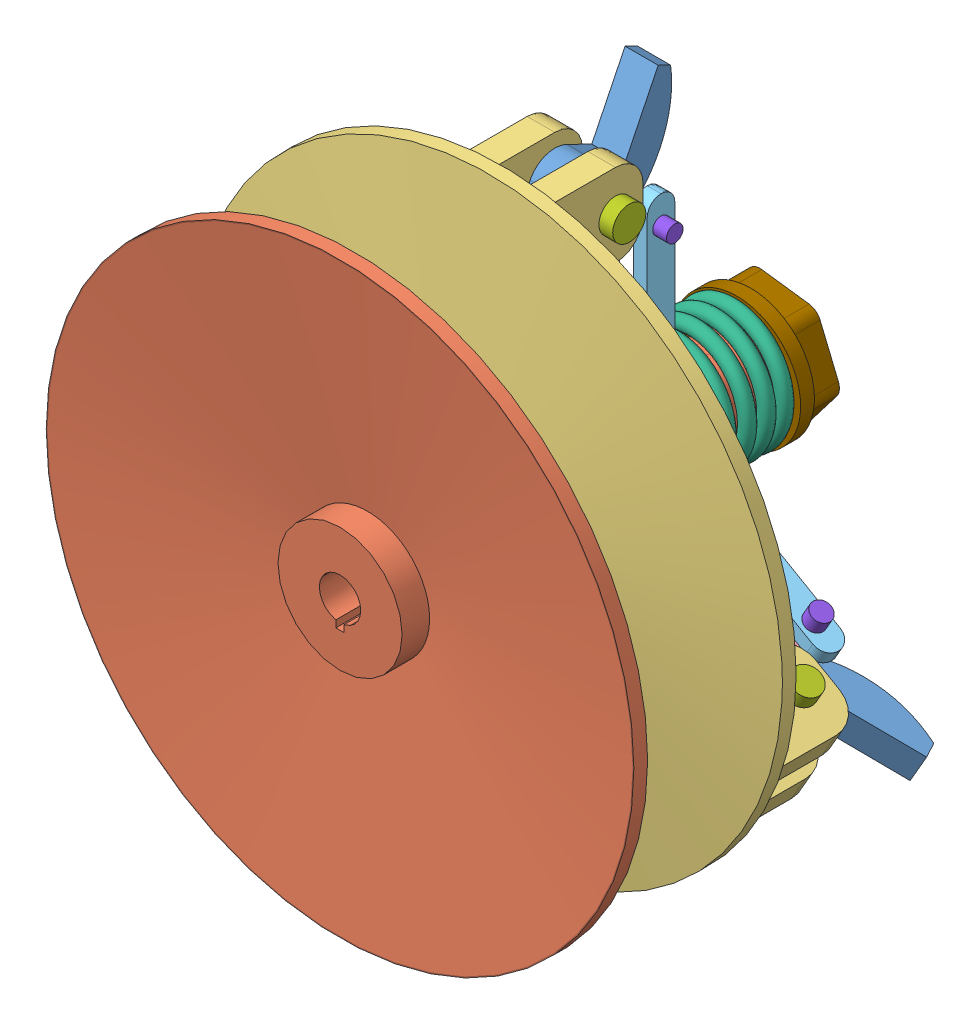
SolidWorks assembly Assembly primary pulley, configuration Default. Lengths in mm.
Overall size (221.83 231.11 158.84).
17 component instances, 9 part files, 40 mates.
Components (placement in the parent):
- cam-1: cam [Default] at (-288.314 -18.7579 216.225) x (0 0.898113 -0.439766) z (-1 0 0) size (47.5 32.18 12)
- primary fix pulley-1: primary fix pulley [Default] at (-294.314 -109.6854 231.0949) size (213 213 158.84)
- primary movable pulley-1: primary movable pulley [Default] at (-294.314 -109.6854 232.2585) size (213 213 50)
- roller-1: roller [Default] at (-286.814 -38.1854 187.2585) x (0 0 1) z (-1 0 0) size (12 12 15)
- spider-1: spider [Default] at (-294.314 -109.6854 182.2585) size (153.66 133.08 15)
- spring-1: spring [Default] at (-294.3124 -109.6827 147.2585) x (-0.215743 -0.97645 0) z (-0.97645 0.215743 0) size (46.49 35 46.31)
- temo bolt 10-1: temo bolt 10 [Default] at (-315.314 -23.1854 207.2585) x (0 -0.924225 -0.381849) z (1 0 0) size (12 12 42)
- temp bolt 6-1: temp bolt 6 [Default] at (-306.814 -38.1854 187.2585) x (0 0 -1) z (1 0 0) size (7 7 35)
- temo bolt 10-27: temo bolt 10 [Default] at (-358.7252 -171.122 207.2585) x (-0.862029 -0.497693 -0.09596) z (-0.5 0.866025 0) size (12 12 42)
- cam-27: cam [Default] at (-376.0596 -149.9531 216.225) x (-0.777788 -0.449056 -0.439766) z (0.5 -0.866025 0) size (47.5 32.18 12)
- cam-28: cam [Default] at (-218.5685 -160.3454 216.225) x (0.777788 -0.449056 -0.439766) z (0.5 0.866025 0) size (47.5 32.18 12)
- temo bolt 10-28: temo bolt 10 [Default] at (-208.9028 -134.7489 207.2585) x (-0.860588 0.496861 0.111883) z (-0.5 -0.866025 0) size (12 12 42)
- temp bolt 6-2: temp bolt 6 [Default] at (-349.9848 -156.2608 187.2585) x (-0.355611 -0.205312 -0.911805) z (-0.5 0.866025 0) size (7 7 35)
- roller-2: roller [Default] at (-352.4848 -151.9306 187.2585) x (0.738529 0.42639 -0.522271) z (-0.5 0.866025 0) size (12 12 15)
- temp bolt 6-4: temp bolt 6 [Default] at (-226.1432 -134.6101 187.2585) x (-0.455022 0.262707 -0.850846) z (-0.5 -0.866025 0) size (7 7 35)
- roller-4: roller [Default] at (-228.6432 -138.9403 187.2585) x (0.833101 -0.480991 -0.273113) z (-0.5 -0.866025 0) size (12 12 15)
- Lockpin-1: Lockpin [Default] at (-294.314 -109.6854 142.2585) x (-0.923728 -0.383049 0) z (0 0 -1) size (46.19 46.19 15)
Mates (geometry in assembly coordinates):
- Coincident1: coincident anti-aligned: plane of primary fix pulley-1 through (-306.814 -107.1854 132.2585) normal (-1 0 0); plane of primary movable pulley-1 through (-306.814 -107.1854 242.2585) normal (1 0 0)
- Coincident2: coincident anti-aligned: plane of primary fix pulley-1 through (-291.814 -97.1854 132.2585) normal (0 1 0); plane of primary movable pulley-1 through (-291.814 -97.1854 242.2585) normal (0 -1 0)
- Coincident3: coincident anti-aligned: plane of primary fix pulley-1 through (-306.814 -107.1854 132.2585) normal (-1 0 0); plane of spider-1 through (-306.814 -107.1854 192.2585) normal (1 0 0)
- Coincident4: coincident anti-aligned: plane of primary fix pulley-1 through (-291.814 -97.1854 132.2585) normal (0 1 0); plane of spider-1 through (-296.814 -97.1854 192.2585) normal (0 -1 0)
- Coincident5: coincident anti-aligned: plane of primary fix pulley-1 through (-306.814 -107.1854 132.2585) normal (-1 0 0); plane of spider-1 through (-306.814 -107.1854 192.2585) normal (1 0 0)
- Coincident6: coincident aligned: cylinder of temo bolt 10-1 through (-278.314 -23.1854 207.2585) axis (-1 0 0) radius 5; circle of primary movable pulley-1
- Coincident7: coincident anti-aligned: circle of primary movable pulley-1; plane of temo bolt 10-1 through (-278.314 -23.1854 207.2585) normal (-1 0 0)
- Concentric3: concentric anti-aligned: cylinder of cam-1 through (-300.314 -23.1854 207.2585) axis (1 0 0) radius 5.0001; cylinder of temo bolt 10-1 through (-278.314 -23.1854 207.2585) axis (-1 0 0) radius 5
- Coincident9: coincident anti-aligned: plane of cam-1 through (-300.314 -1.7043 219.7861) normal (-1 0 0); plane of primary movable pulley-1 through (-300.314 -8.1854 247.2595) normal (1 0 0)
- Concentric4: concentric anti-aligned: cylinder of spider-1 through (-310.814 -38.1854 187.2585) axis (1 0 0) radius 3; cylinder of temp bolt 6-1 through (-276.814 -38.1854 187.2585) axis (-1 0 0) radius 3
- Coincident10: coincident anti-aligned: circle of spider-1; plane of temp bolt 6-1 through (-306.814 -38.1854 187.2585) normal (1 0 0)
- Concentric5: concentric anti-aligned: cylinder of roller-1 through (-301.814 -38.1854 187.2585) axis (1 0 0) radius 3; cylinder of temp bolt 6-1 through (-276.814 -38.1854 187.2585) axis (-1 0 0) radius 3
- Coincident11: coincident aligned: plane of roller-1 through (-301.814 -38.1854 187.2585) normal (-1 0 0); circle of spider-1
- Concentric31: concentric aligned: cylinder of primary movable pulley-1 through (-454.743 -4.8143 207.2585) axis (0.5 -0.866025 0) radius 5; cylinder of temo bolt 10-27 through (-377.2252 -139.079 207.2585) axis (0.5 -0.866025 0) radius 5
- Coincident14: coincident aligned: circle of primary movable pulley-1; circle of temo bolt 10-27
- Concentric32: concentric anti-aligned: cylinder of temo bolt 10-27 through (-377.2252 -139.079 207.2585) axis (0.5 -0.866025 0) radius 5; cylinder of cam-27 through (-366.2252 -158.1316 207.2585) axis (-0.5 0.866025 0) radius 5.0001
- Concentric33: concentric aligned: circle of primary movable pulley-1; circle of cam-27
- Concentric34: concentric anti-aligned: circle of primary movable pulley-1; circle of cam-27
- Coincident15: coincident anti-aligned: plane of primary movable pulley-1 through (-379.2156 -165.6316 247.2595) normal (-0.5 0.866025 0); plane of cam-27 through (-384.8284 -168.8722 219.7861) normal (0.5 -0.866025 0)
- Concentric35: concentric aligned: cylinder of primary movable pulley-1 through (-288.9206 -273.3438 207.2585) axis (0.5 0.866025 0) radius 5; cylinder of temo bolt 10-28 through (-227.4028 -166.7919 207.2585) axis (0.5 0.866025 0) radius 5
- Coincident16: coincident anti-aligned: circle of primary movable pulley-1; plane of temo bolt 10-28 through (-227.4028 -166.7919 207.2585) normal (0.5 0.866025 0)
- Concentric36: concentric anti-aligned: cylinder of cam-28 through (-216.4028 -147.7393 207.2585) axis (-0.5 -0.866025 0) radius 5.0001; cylinder of temo bolt 10-28 through (-227.4028 -166.7919 207.2585) axis (0.5 0.866025 0) radius 5
- Coincident17: coincident anti-aligned: plane of primary movable pulley-1 through (-203.4124 -155.2393 247.2595) normal (-0.5 -0.866025 0); plane of cam-28 through (-197.7996 -158.4799 219.7861) normal (0.5 0.866025 0)
- Concentric37: concentric aligned: cylinder of temp bolt 6-2 through (-364.9848 -130.28 187.2585) axis (0.5 -0.866025 0) radius 3; cylinder of roller-2 through (-359.9848 -138.9403 187.2585) axis (0.5 -0.866025 0) radius 3
- Concentric38: concentric anti-aligned: cylinder of spider-1 through (-347.9848 -159.7249 187.2585) axis (-0.5 0.866025 0) radius 3; cylinder of temp bolt 6-2 through (-364.9848 -130.28 187.2585) axis (0.5 -0.866025 0) radius 3
- Coincident18: coincident anti-aligned: circle of spider-1; plane of temp bolt 6-2 through (-349.9848 -156.2608 187.2585) normal (-0.5 0.866025 0)
- Coincident19: coincident anti-aligned: circle of spider-1; plane of roller-2 through (-359.9848 -138.9403 187.2585) normal (-0.5 0.866025 0)
- Concentric40: concentric aligned: cylinder of temp bolt 6-4 through (-241.1432 -160.5909 187.2585) axis (0.5 0.866025 0) radius 3; cylinder of roller-4 through (-236.1432 -151.9306 187.2585) axis (0.5 0.866025 0) radius 3
- Concentric41: concentric anti-aligned: circle of spider-1; cylinder of temp bolt 6-4 through (-241.1432 -160.5909 187.2585) axis (0.5 0.866025 0) radius 3
- Coincident21: coincident anti-aligned: circle of spider-1; plane of temp bolt 6-4 through (-226.1432 -134.6101 187.2585) normal (-0.5 -0.866025 0)
- Coincident22: coincident anti-aligned: circle of spider-1; plane of roller-4 through (-236.1432 -151.9306 187.2585) normal (-0.5 -0.866025 0)
- Tangent3: tangent anti-aligned: cylinder of cam-27 through (-384.8284 -168.8722 219.7861) axis (-0.5 0.866025 0) radius 42.8765; cylinder of roller-2 through (-359.9848 -138.9403 187.2585) axis (0.5 -0.866025 0) radius 6
- Tangent4: tangent anti-aligned: cylinder of cam-28 through (-197.7996 -158.4799 219.7861) axis (-0.5 -0.866025 0) radius 42.8765; cylinder of roller-4 through (-236.1432 -151.9306 187.2585) axis (0.5 0.866025 0) radius 6
- Tangent6: tangent anti-aligned: cylinder of cam-1 through (-300.314 -1.7043 219.7861) axis (1 0 0) radius 42.8765; cylinder of roller-1 through (-301.814 -38.1854 187.2585) axis (1 0 0) radius 6
- Coincident23: coincident anti-aligned: plane of spider-1 through (-294.314 -109.6854 182.2585) normal (0 0 -1); plane of spring-1 through (-294.3124 -109.6827 182.2585) normal (0 0 1)
- Tangent7: tangent aligned: cylinder of spider-1 through (-294.314 -109.6854 177.2585) axis (0 0 1) radius 22.5; face of spring-1
- Coincident24: coincident aligned: plane of primary fix pulley-1 through (-291.814 -112.1854 132.2585) normal (0 0 -1); plane of Lockpin-1 through (-294.314 -109.6854 132.2585) normal (0 0 -1)
- Concentric42: concentric aligned: cylinder of primary movable pulley-1 through (-294.314 -109.6854 242.2585) axis (0 0 -1) radius 25; cylinder of Lockpin-1 through (-294.314 -109.6854 147.2585) axis (0 0 -1) radius 23.094
- Coincident25: coincident anti-aligned: plane of spring-1 through (-294.3124 -109.6827 147.2585) normal (0 0 -1); plane of Lockpin-1 through (-294.314 -109.6854 147.2585) normal (0 0 1)
- LimitDistance1: limit distance = 10 mm anti-aligned: plane of spider-1 through (-294.314 -109.6854 192.2585) normal (0 0 1); plane of primary movable pulley-1 through (-294.314 -109.6854 202.2585) normal (0 0 -1)
